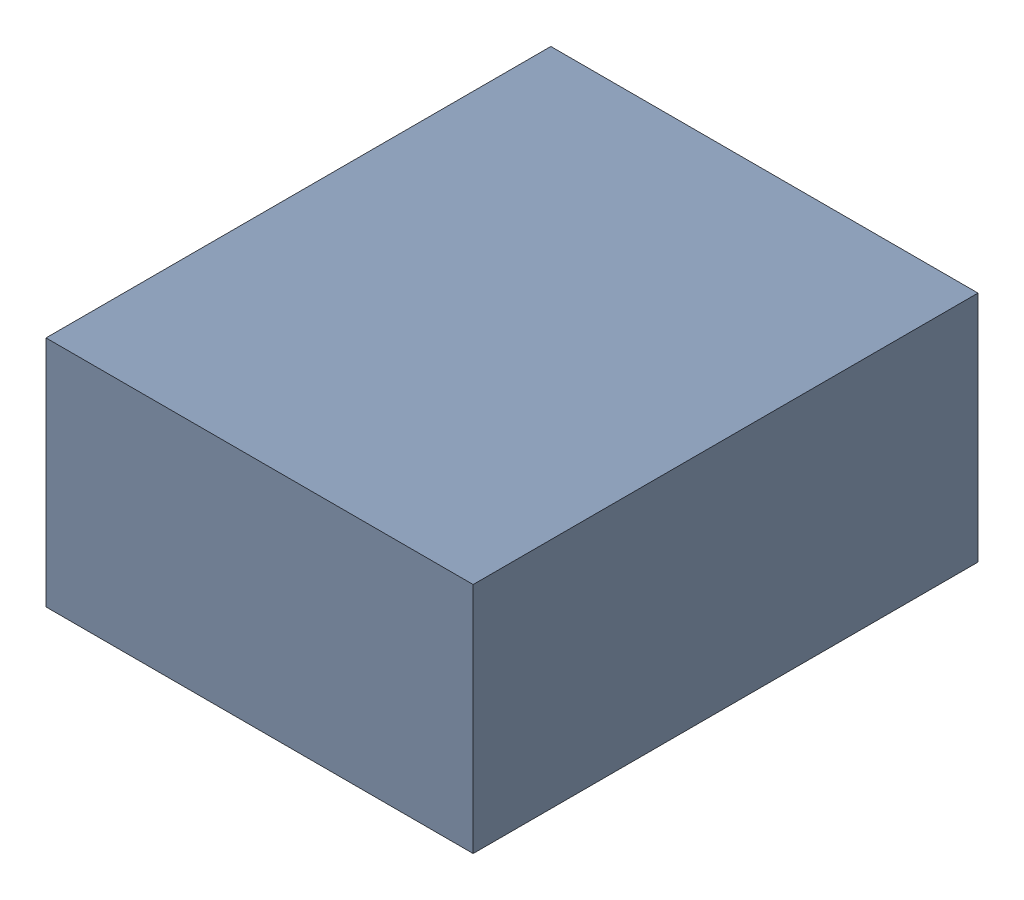
SolidWorks assembly C4, configuration Standard. Lengths in mm.
Overall size (1.1 0.6 1.3).
2 component instances, 1 part files, 0 mates.
Components (placement in the parent):
- 885542240-1: 885542240 [Standard] at (-17.8 -1.6 0) size (1.1 0.6 1.3)
  - Extruded_28-1: Extruded_28 [Standard] at origin size (1.1 0.6 1.3)
